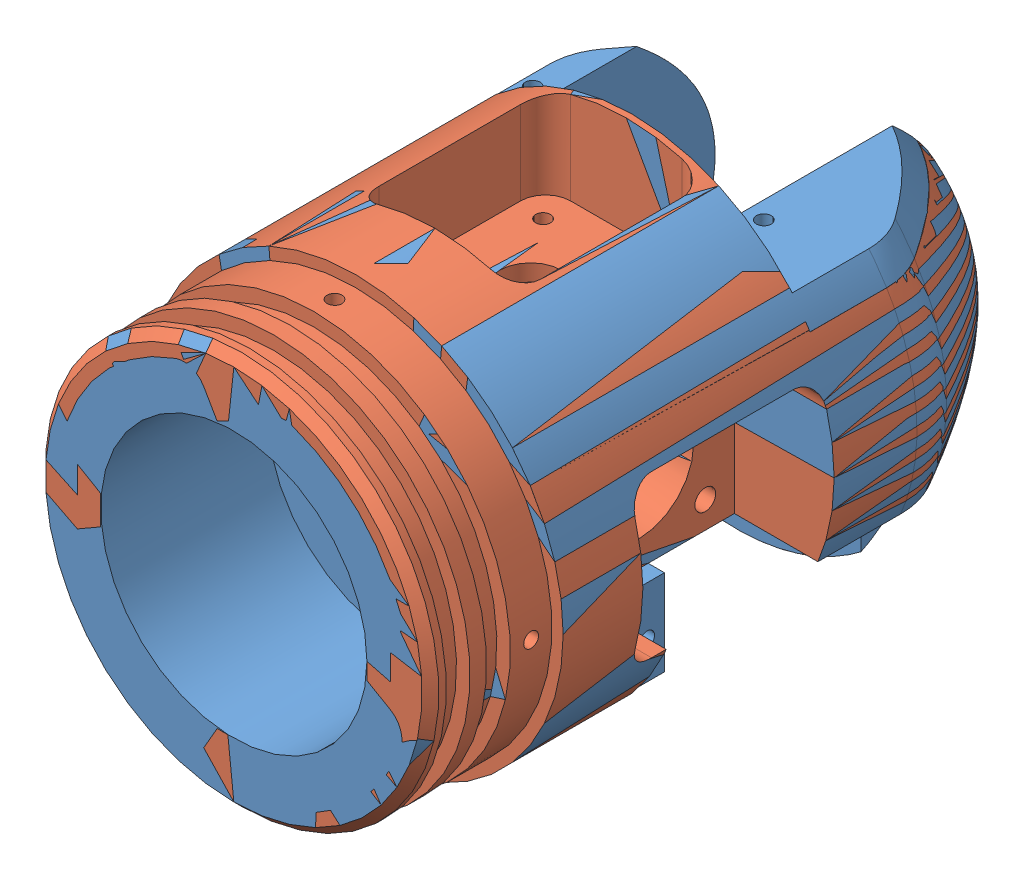
SolidWorks assembly Assem3, configuration Default. Lengths in mm.
Overall size (63.5 63.5 100.33).
2 component instances, 2 part files, 1 mates.
Components (placement in the parent):
- EXK-01-0006_R--1: EXK-01-0006_R- [Default] at (-89.4045 -8.864 95.1102) size (63.5 63.5 100.33)
- EXK-01-0006-1: EXK-01-0006 [Default] at (-89.4045 -8.864 95.1102) size (63.5 63.5 100.33)
Mates (geometry in assembly coordinates):
- Coincident1: coordinate: point of EXK-01-0006_R--1; point of EXK-01-0006-1
